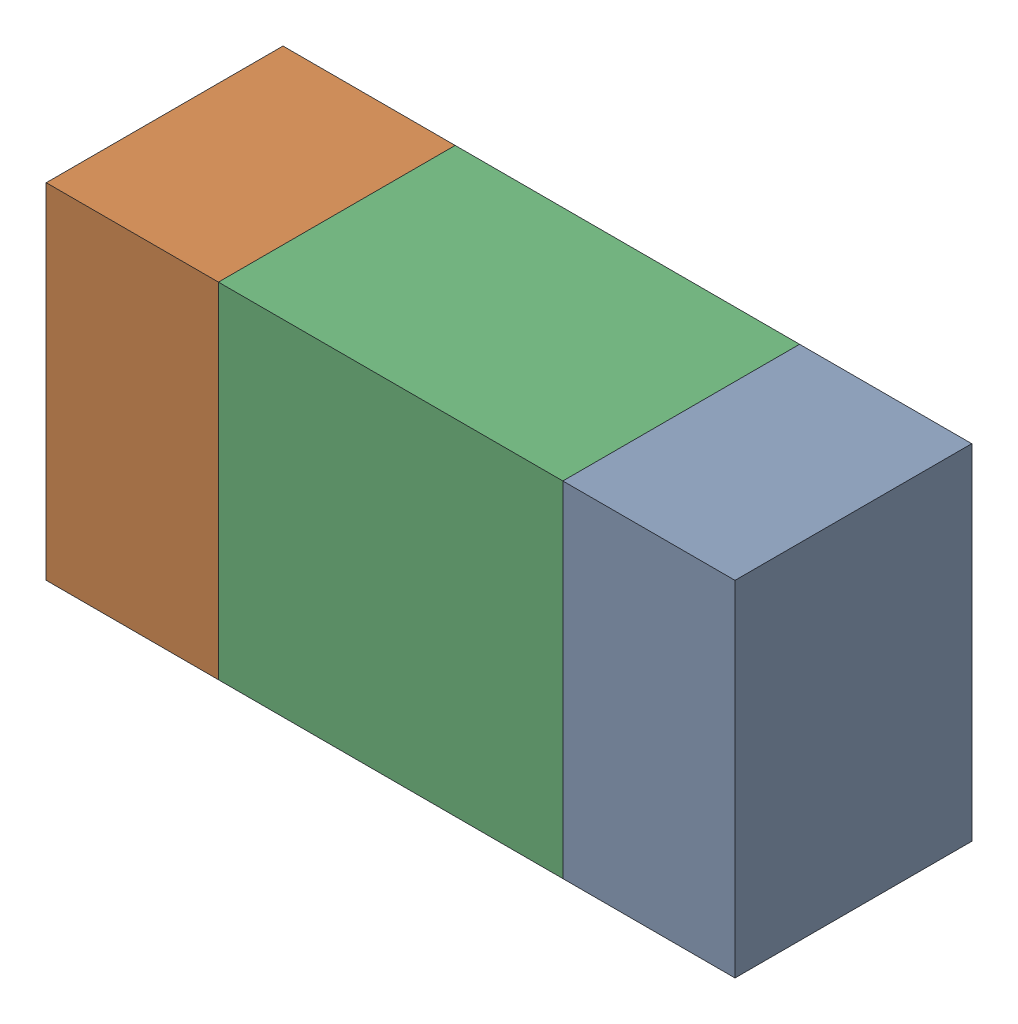
SolidWorks assembly R22, configuration ﾃﾞﾌｫﾙﾄ. Lengths in mm.
Overall size (1.6 0.8 0.55).
6 component instances, 2 part files, 0 mates.
Components (placement in the parent):
- 689261512-1: 689261512 [ﾃﾞﾌｫﾙﾄ] at (6.3149 19.0501 -1.7503) size (0.4 0.8 0.55)
  - Extruded_32-1: Extruded_32 [ﾃﾞﾌｫﾙﾄ] at origin size (0.4 0.8 0.55)
- 689261512-2: 689261512 [ﾃﾞﾌｫﾙﾄ] at (5.1149 19.0501 -1.7503) size (0.4 0.8 0.55)
  - Extruded_32-1: Extruded_32 [ﾃﾞﾌｫﾙﾄ] at origin size (0.4 0.8 0.55)
- 689261648-1: 689261648 [ﾃﾞﾌｫﾙﾄ] at (5.715 19.0501 -1.7503) size (0.8 0.8 0.55)
  - Extruded_33-1: Extruded_33 [ﾃﾞﾌｫﾙﾄ] at origin size (0.8 0.8 0.55)
